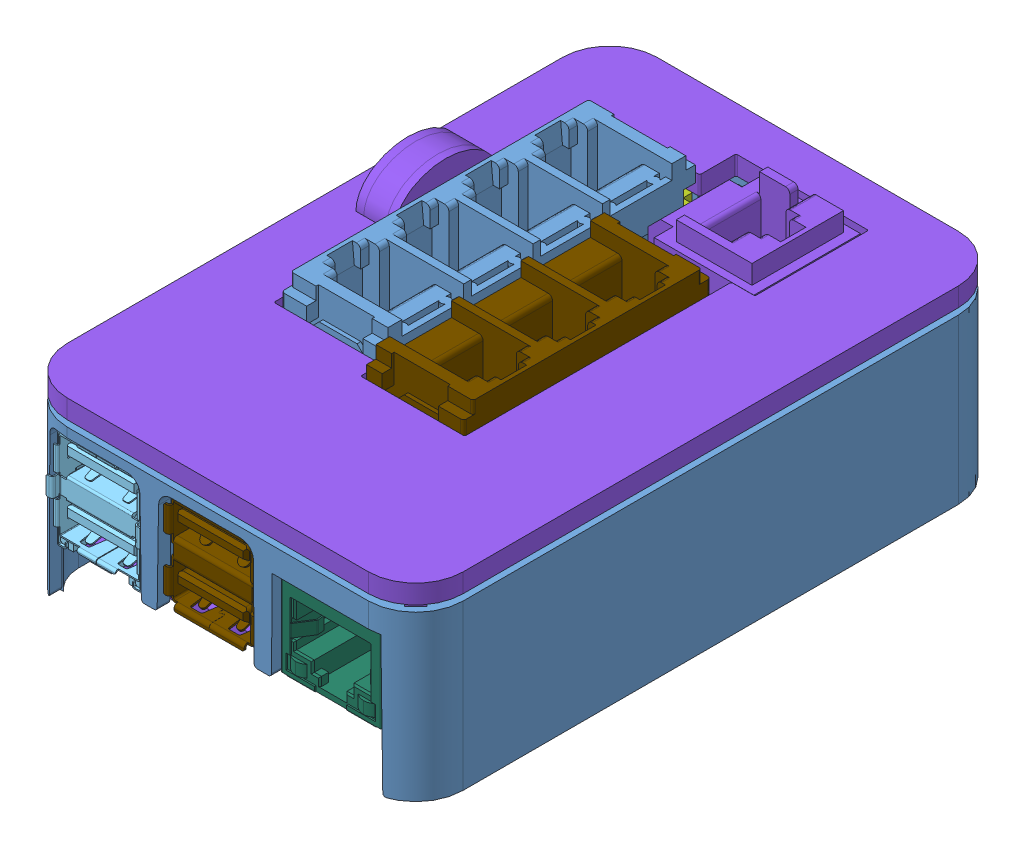
SolidWorks assembly Assemblage_2print, configuration Défaut. Lengths in mm.
Overall size (62.75 36.13 93.5).
237 component instances, 44 part files, 9 mates.
Components (placement in the parent):
- RPI4_Canakit_Case-1: RPI4_Canakit_Case [Défaut] at (-18.9096 -7.6584 0) size (62.75 26 93.5)
- Mainboard_Rpi4-1: Mainboard_Rpi4 [Défaut] at (4.6154 9.8935 -38.925) x (0 0 1) z (0 1 0) size (66 57.75 22.04)
  - Mainboard_Rpi4.step-1: Mainboard_Rpi4.step [Défaut] at origin size (66 57.75 22.04)
    - J5.step-1: J5.step [Défaut] at origin size (50.8 7.2 4.95)
      - m20-7812045_asm.step-1: m20-7812045_asm.step [Défaut] at (4.8701 0.0001 -1.7297) x (1 0 0) z (0 1 0) size (50.8 4.95 7.2)
        - M20-78120_MOULD.step-1: M20-78120_MOULD.step [Défaut] at origin size (50.8 4.95 5.08)
        - M20-781_CONTACT.step-1: M20-781_CONTACT.step [Défaut] at (-0.75 1.3 -2.135) size (1.5 2.8 2.83)
        - M20-781_CONTACT.step-2: M20-781_CONTACT.step [Défaut] at (1.79 1.3 -2.135) size (1.5 2.8 2.83)
        - M20-781_CONTACT.step-3: M20-781_CONTACT.step [Défaut] at (4.33 1.3 -2.135) size (1.5 2.8 2.83)
        - M20-781_CONTACT.step-4: M20-781_CONTACT.step [Défaut] at (6.87 1.3 -2.135) size (1.5 2.8 2.83)
        - M20-781_CONTACT.step-5: M20-781_CONTACT.step [Défaut] at (9.41 1.3 -2.135) size (1.5 2.8 2.83)
        - M20-781_CONTACT.step-6: M20-781_CONTACT.step [Défaut] at (11.95 1.3 -2.135) size (1.5 2.8 2.83)
        - M20-781_CONTACT.step-7: M20-781_CONTACT.step [Défaut] at (14.49 1.3 -2.135) size (1.5 2.8 2.83)
        - M20-781_CONTACT.step-8: M20-781_CONTACT.step [Défaut] at (17.03 1.3 -2.135) size (1.5 2.8 2.83)
        - M20-781_CONTACT.step-9: M20-781_CONTACT.step [Défaut] at (19.57 1.3 -2.135) size (1.5 2.8 2.83)
        - M20-781_CONTACT.step-10: M20-781_CONTACT.step [Défaut] at (22.11 1.3 -2.135) size (1.5 2.8 2.83)
        - M20-781_CONTACT.step-11: M20-781_CONTACT.step [Défaut] at (24.65 1.3 -2.135) size (1.5 2.8 2.83)
        - M20-781_CONTACT.step-12: M20-781_CONTACT.step [Défaut] at (27.19 1.3 -2.135) size (1.5 2.8 2.83)
        - M20-781_CONTACT.step-13: M20-781_CONTACT.step [Défaut] at (29.73 1.3 -2.135) size (1.5 2.8 2.83)
        - M20-781_CONTACT.step-14: M20-781_CONTACT.step [Défaut] at (32.27 1.3 -2.135) size (1.5 2.8 2.83)
        - M20-781_CONTACT.step-15: M20-781_CONTACT.step [Défaut] at (34.81 1.3 -2.135) size (1.5 2.8 2.83)
        - M20-781_CONTACT.step-16: M20-781_CONTACT.step [Défaut] at (37.35 1.3 -2.135) size (1.5 2.8 2.83)
        - M20-781_CONTACT.step-17: M20-781_CONTACT.step [Défaut] at (39.89 1.3 -2.135) size (1.5 2.8 2.83)
        - M20-781_CONTACT.step-18: M20-781_CONTACT.step [Défaut] at (42.43 1.3 -2.135) size (1.5 2.8 2.83)
        - M20-781_CONTACT.step-19: M20-781_CONTACT.step [Défaut] at (44.97 1.3 -2.135) size (1.5 2.8 2.83)
        - M20-781_CONTACT.step-20: M20-781_CONTACT.step [Défaut] at (47.51 1.3 -2.135) size (1.5 2.8 2.83)
        - M20-781_CONTACT.step-21: M20-781_CONTACT.step [Défaut] at (0.75 1.3 2.135) x (-1 0 0) z (0 0 -1) size (1.5 2.8 2.83)
        - M20-781_CONTACT.step-22: M20-781_CONTACT.step [Défaut] at (3.29 1.3 2.135) x (-1 0 0) z (0 0 -1) size (1.5 2.8 2.83)
        - M20-781_CONTACT.step-23: M20-781_CONTACT.step [Défaut] at (5.83 1.3 2.135) x (-1 0 0) z (0 0 -1) size (1.5 2.8 2.83)
        - M20-781_CONTACT.step-24: M20-781_CONTACT.step [Défaut] at (8.37 1.3 2.135) x (-1 0 0) z (0 0 -1) size (1.5 2.8 2.83)
        - M20-781_CONTACT.step-25: M20-781_CONTACT.step [Défaut] at (10.91 1.3 2.135) x (-1 0 0) z (0 0 -1) size (1.5 2.8 2.83)
        - M20-781_CONTACT.step-26: M20-781_CONTACT.step [Défaut] at (13.45 1.3 2.135) x (-1 0 0) z (0 0 -1) size (1.5 2.8 2.83)
        - M20-781_CONTACT.step-27: M20-781_CONTACT.step [Défaut] at (15.99 1.3 2.135) x (-1 0 0) z (0 0 -1) size (1.5 2.8 2.83)
        - M20-781_CONTACT.step-28: M20-781_CONTACT.step [Défaut] at (18.53 1.3 2.135) x (-1 0 0) z (0 0 -1) size (1.5 2.8 2.83)
        - M20-781_CONTACT.step-29: M20-781_CONTACT.step [Défaut] at (21.07 1.3 2.135) x (-1 0 0) z (0 0 -1) size (1.5 2.8 2.83)
        - M20-781_CONTACT.step-30: M20-781_CONTACT.step [Défaut] at (23.61 1.3 2.135) x (-1 0 0) z (0 0 -1) size (1.5 2.8 2.83)
        - M20-781_CONTACT.step-31: M20-781_CONTACT.step [Défaut] at (26.15 1.3 2.135) x (-1 0 0) z (0 0 -1) size (1.5 2.8 2.83)
        - M20-781_CONTACT.step-32: M20-781_CONTACT.step [Défaut] at (28.69 1.3 2.135) x (-1 0 0) z (0 0 -1) size (1.5 2.8 2.83)
        - M20-781_CONTACT.step-33: M20-781_CONTACT.step [Défaut] at (31.23 1.3 2.135) x (-1 0 0) z (0 0 -1) size (1.5 2.8 2.83)
        - M20-781_CONTACT.step-34: M20-781_CONTACT.step [Défaut] at (33.77 1.3 2.135) x (-1 0 0) z (0 0 -1) size (1.5 2.8 2.83)
        - M20-781_CONTACT.step-35: M20-781_CONTACT.step [Défaut] at (36.31 1.3 2.135) x (-1 0 0) z (0 0 -1) size (1.5 2.8 2.83)
        - M20-781_CONTACT.step-36: M20-781_CONTACT.step [Défaut] at (38.85 1.3 2.135) x (-1 0 0) z (0 0 -1) size (1.5 2.8 2.83)
        - M20-781_CONTACT.step-37: M20-781_CONTACT.step [Défaut] at (41.39 1.3 2.135) x (-1 0 0) z (0 0 -1) size (1.5 2.8 2.83)
        - M20-781_CONTACT.step-38: M20-781_CONTACT.step [Défaut] at (43.93 1.3 2.135) x (-1 0 0) z (0 0 -1) size (1.5 2.8 2.83)
        - M20-781_CONTACT.step-39: M20-781_CONTACT.step [Défaut] at (46.47 1.3 2.135) x (-1 0 0) z (0 0 -1) size (1.5 2.8 2.83)
        - M20-781_CONTACT.step-40: M20-781_CONTACT.step [Défaut] at (49.01 1.3 2.135) x (-1 0 0) z (0 0 -1) size (1.5 2.8 2.83)
    - C3.step-1: C3.step [Défaut] at origin size (2.2 1.45 1.4)
      - 870407824.step-1: 870407824.step [Défaut] at (-0.508 -11.732 -2.9519) size (2.2 1.45 1.4)
        - Extruded.step-1: Extruded.step [Défaut] at origin size (2.2 1.45 1.4)
    - C2.step-1: C2.step [Défaut] at origin size (2.2 1.45 1.4)
      - 870407824.step-1: 870407824.step [Défaut] at (50.8 -29.718 -2.9519) size (2.2 1.45 1.4)
        - Extruded.step-1: Extruded.step [Défaut] at origin size (2.2 1.45 1.4)
    - U10.step-1: U10.step [Défaut] at origin size (2 2 0.8)
      - 870408096.step-1: 870408096.step [Défaut] at (7.747 -16.873 -2.4519) size (2 2 0.8)
        - Extruded-0.step-1: Extruded-0.step [Défaut] at origin size (2 2 0.8)
    - U9.step-1: U9.step [Défaut] at origin size (2 2 0.8)
      - 870408096.step-1: 870408096.step [Défaut] at (11.049 -16.873 -2.4519) size (2 2 0.8)
        - Extruded-0.step-1: Extruded-0.step [Défaut] at origin size (2 2 0.8)
    - U8.step-1: U8.step [Défaut] at origin size (2 2 0.8)
      - 870408096.step-1: 870408096.step [Défaut] at (4.445 -16.873 -2.4519) size (2 2 0.8)
        - Extruded-0.step-1: Extruded-0.step [Défaut] at origin size (2 2 0.8)
    - R3.step-1: R3.step [Défaut] at origin size (1.4 2.15 0.7)
      - 870408368.step-1: 870408368.step [Défaut] at (8.89 -9.779 -2.2519) size (1.4 2.15 0.7)
        - Extruded-1.step-1: Extruded-1.step [Défaut] at origin size (1.4 2.15 0.7)
    - Q8.step-1: Q8.step [Défaut] at origin size (2.2 1.35 1)
      - 870406736.step-1: 870406736.step [Défaut] at (1.524 -8.938 -2.6519) size (2.2 1.35 1)
        - Extruded-2.step-1: Extruded-2.step [Défaut] at origin size (2.2 1.35 1)
    - J3.step-1: J3.step [Défaut] at origin size (20.9 19.8 19.5)
      - TM3RA-88_RGB13278208.step-1: TM3RA-88_RGB13278208.step [Défaut] at (8.2551 -24.0349 12.5) x (1 0 0) z (0 0 1) size (20.9 19.8 19.5)
    - U7.step-1: U7.step [Défaut] at origin size (2 2 0.8)
      - 870408096.step-1: 870408096.step [Défaut] at (26.369 -39.41 -2.4519) size (2 2 0.8)
        - Extruded-0.step-1: Extruded-0.step [Défaut] at origin size (2 2 0.8)
    - U6.step-1: U6.step [Défaut] at origin size (2 2 0.8)
      - 870408096.step-1: 870408096.step [Défaut] at (49.099 -15.349 -2.4519) size (2 2 0.8)
        - Extruded-0.step-1: Extruded-0.step [Défaut] at origin size (2 2 0.8)
    - U5.step-1: U5.step [Défaut] at origin size (2 2 0.8)
      - 870408096.step-1: 870408096.step [Défaut] at (37.291 -39.41 -2.4519) size (2 2 0.8)
        - Extruded-0.step-1: Extruded-0.step [Défaut] at origin size (2 2 0.8)
    - U4.step-1: U4.step [Défaut] at origin size (2 2 0.8)
      - 870408096.step-1: 870408096.step [Défaut] at (38.05 -15.349 -2.4519) size (2 2 0.8)
        - Extruded-0.step-1: Extruded-0.step [Défaut] at origin size (2 2 0.8)
    - U3.step-1: U3.step [Défaut] at origin size (2 2 0.8)
      - 870408096.step-1: 870408096.step [Défaut] at (15.32 -39.41 -2.4519) size (2 2 0.8)
        - Extruded-0.step-1: Extruded-0.step [Défaut] at origin size (2 2 0.8)
    - U2.step-1: U2.step [Défaut] at origin size (2 2 0.8)
      - 870408096.step-1: 870408096.step [Défaut] at (48.34 -39.41 -2.4519) size (2 2 0.8)
        - Extruded-0.step-1: Extruded-0.step [Défaut] at origin size (2 2 0.8)
    - U1.step-1: U1.step [Défaut] at origin size (2 2 0.8)
      - 870408096.step-1: 870408096.step [Défaut] at (27.128 -15.349 -2.4519) size (2 2 0.8)
        - Extruded-0.step-1: Extruded-0.step [Défaut] at origin size (2 2 0.8)
    - Q7.step-1: Q7.step [Défaut] at origin size (1.35 2.2 1)
      - 870407280.step-1: 870407280.step [Défaut] at (10.24 -39.16 -2.6519) size (1.35 2.2 1)
        - Extruded-3.step-1: Extruded-3.step [Défaut] at origin size (1.35 2.2 1)
    - Q6.step-1: Q6.step [Défaut] at origin size (1.35 2.2 1)
      - 870407280.step-1: 870407280.step [Défaut] at (21.289 -39.16 -2.6519) size (1.35 2.2 1)
        - Extruded-3.step-1: Extruded-3.step [Défaut] at origin size (1.35 2.2 1)
    - Q5.step-1: Q5.step [Défaut] at origin size (1.35 2.2 1)
      - 870407280.step-1: 870407280.step [Défaut] at (32.211 -39.16 -2.6519) size (1.35 2.2 1)
        - Extruded-3.step-1: Extruded-3.step [Défaut] at origin size (1.35 2.2 1)
    - Q4.step-1: Q4.step [Défaut] at origin size (1.35 2.2 1)
      - 870407280.step-1: 870407280.step [Défaut] at (43.26 -39.16 -2.6519) size (1.35 2.2 1)
        - Extruded-3.step-1: Extruded-3.step [Défaut] at origin size (1.35 2.2 1)
    - Q3.step-1: Q3.step [Défaut] at origin size (1.35 2.2 1)
      - 870407280.step-1: 870407280.step [Défaut] at (54.179 -15.599 -2.6519) size (1.35 2.2 1)
        - Extruded-3.step-1: Extruded-3.step [Défaut] at origin size (1.35 2.2 1)
    - Q2.step-1: Q2.step [Défaut] at origin size (1.35 2.2 1)
      - 870407280.step-1: 870407280.step [Défaut] at (43.13 -15.599 -2.6519) size (1.35 2.2 1)
        - Extruded-3.step-1: Extruded-3.step [Défaut] at origin size (1.35 2.2 1)
    - Q1.step-1: Q1.step [Défaut] at origin size (1.35 2.2 1)
      - 870407280.step-1: 870407280.step [Défaut] at (32.208 -15.599 -2.6519) size (1.35 2.2 1)
        - Extruded-3.step-1: Extruded-3.step [Défaut] at origin size (1.35 2.2 1)
    - R2.step-1: R2.step [Défaut] at origin size (2.15 1.4 0.7)
      - 870406464.step-1: 870406464.step [Défaut] at (43.514 -45.974 -2.2519) size (2.15 1.4 0.7)
        - Extruded-4.step-1: Extruded-4.step [Défaut] at origin size (2.15 1.4 0.7)
    - R1.step-1: R1.step [Défaut] at origin size (2.15 1.4 0.7)
      - 870406464.step-1: 870406464.step [Défaut] at (43.514 -48.26 -2.2519) size (2.15 1.4 0.7)
        - Extruded-4.step-1: Extruded-4.step [Défaut] at origin size (2.15 1.4 0.7)
    - U11.step-1: U11.step [Défaut] at origin size (4.91 6.03 1.75)
      - 873278928.step-1: 873278928.step [Défaut] at (0.635 -37.084 -1.5519) x (0 -1 0) z (0 0 -1) size (6.03 4.9 1.75)
        - Body.step-1: Body.step [Défaut] at (-1.95 -2.45 0) size (3.91 4.9 1.65)
          - Open_CASCADE_STEP_translator_6.8_10.2.1.step-1: Open_CASCADE_STEP_translator_6.8_10.2.1.step [Défaut] at origin size (3.91 4.9 1.65)
        - Open_CASCADE_STEP_translator_6.8_10.1.step-1: Open_CASCADE_STEP_translator_6.8_10.1.step [Défaut] at (-1.95 -2.45 0.001) size (0.5 0.5 0.01)
        - Leader.step-1: Leader.step [Défaut] at (-1.95 -1.905 0) x (-1 0 0) z (0 0 1) size (1.06 0.41 0.97)
        - Leader.step-2: Leader.step [Défaut] at (-1.95 -0.635 0) x (-1 0 0) z (0 0 1) size (1.06 0.41 0.97)
        - Leader.step-3: Leader.step [Défaut] at (-1.95 0.635 0) x (-1 0 0) z (0 0 1) size (1.06 0.41 0.97)
        - Leader.step-4: Leader.step [Défaut] at (-1.95 1.905 0) x (-1 0 0) z (0 0 1) size (1.06 0.41 0.97)
        - Leader.step-5: Leader.step [Défaut] at (1.95 -1.905 0) size (1.06 0.41 0.97)
        - Leader.step-6: Leader.step [Défaut] at (1.95 -0.635 0) size (1.06 0.41 0.97)
        - Leader.step-7: Leader.step [Défaut] at (1.95 0.635 0) size (1.06 0.41 0.97)
        - Leader.step-8: Leader.step [Défaut] at (1.95 1.905 0) size (1.06 0.41 0.97)
    - J4.step-1: J4.step [Défaut] at origin size (15.42 4.78 16.81)
      - BS-1225-PC.step-1: BS-1225-PC.step [Défaut] at (29.2101 -47.371 0) x (-1 0 0) z (0 1 0) size (15.42 16.81 4.78)
    - Cx2.step-1: Cx2.step [Défaut] at origin size (1.45 2.2 1.4)
      - 870404832.step-1: 870404832.step [Défaut] at (0.705 -26.66 -2.9519) size (1.45 2.2 1.4)
        - Extruded-5.step-1: Extruded-5.step [Défaut] at origin size (1.45 2.2 1.4)
    - Cx1.step-1: Cx1.step [Défaut] at origin size (1.45 2.2 1.4)
      - 870404832.step-1: 870404832.step [Défaut] at (-1.795 -26.66 -2.9519) size (1.45 2.2 1.4)
        - Extruded-5.step-1: Extruded-5.step [Défaut] at origin size (1.45 2.2 1.4)
    - C1.step-1: C1.step [Défaut] at origin size (2.2 1.45 1.4)
      - 870407824.step-1: 870407824.step [Défaut] at (-0.545 -42.926 -2.9519) size (2.2 1.45 1.4)
        - Extruded.step-1: Extruded.step [Défaut] at origin size (2.2 1.45 1.4)
    - U12.step-1: U12.step [Défaut] at origin size (3.7 2 0.9)
      - 873282384.step-1: 873282384.step [Défaut] at (-0.545 -30.9968 -1.5519) x (-1 0 0) z (0 0 -1) size (3.7 2 0.9)
        - Body-6.step-1: Body-6.step [Défaut] at (-1.65 -0.8 0) size (3.3 1.6 0.9)
        - bigPin.step-1: bigPin.step [Défaut] at (-1.85 -1 -0.0033) size (1.2 2 0.01)
        - bigPin.step-2: bigPin.step [Défaut] at (0.65 -1 -0.0033) size (1.2 2 0.01)
    - J1.step-1: J1.step [Défaut] at origin size (39.2 15.4 22.04)
      - TM2RE-1818(50)_RGB13278208.step-1: TM2RE-1818(50)_RGB13278208.step [Défaut] at (39.3359 -11.3181 16) x (1 0 0) z (0 0 1) size (39.2 15.4 22.04)
        - TM2RE-1818(50).step-1: TM2RE-1818(50).step [Défaut] at (0 -7.7 0) size (39.2 15.4 22.04)
    - J2.step-1: J2.step [Défaut] at origin size (50.2 15.4 22.04)
      - TM2RE-2424_RGB13278208.step-1: TM2RE-2424_RGB13278208.step [Défaut] at (47.0601 -35.774 16) x (-1 0 0) z (0 0 1) size (50.2 15.4 22.04)
    - P2.step-1: P2.step [Défaut] at origin size (2.54 2.54 5.55)
      - 870406192.step-1: 870406192.step [Défaut] at (0 -4.826 0) size (2.54 2.54 5.55)
        - Extruded-7.step-1: Extruded-7.step [Défaut] at origin size (2.54 2.54 5.55)
    - R4.step-1: R4.step [Défaut] at origin size (1.7 0.95 0.55)
      - 870422376.step-1: 870422376.step [Défaut] at (50.8 -27.7876 -2.1019) size (1.7 0.95 0.55)
        - Extruded-8.step-1: Extruded-8.step [Défaut] at origin size (1.7 0.95 0.55)
    - R5.step-1: R5.step [Défaut] at origin size (1.7 0.95 0.55)
      - 870422376.step-1: 870422376.step [Défaut] at (47.498 -27.7876 -2.1019) size (1.7 0.95 0.55)
        - Extruded-8.step-1: Extruded-8.step [Défaut] at origin size (1.7 0.95 0.55)
    - R6.step-1: R6.step [Défaut] at origin size (1.7 0.95 0.55)
      - 870422376.step-1: 870422376.step [Défaut] at (31.115 -12.7 -2.1019) size (1.7 0.95 0.55)
        - Extruded-8.step-1: Extruded-8.step [Défaut] at origin size (1.7 0.95 0.55)
    - R7.step-1: R7.step [Défaut] at origin size (1.7 0.95 0.55)
      - 870422376.step-1: 870422376.step [Défaut] at (26.162 -12.7 -2.1019) size (1.7 0.95 0.55)
        - Extruded-8.step-1: Extruded-8.step [Défaut] at origin size (1.7 0.95 0.55)
    - R8.step-1: R8.step [Défaut] at origin size (1.7 0.95 0.55)
      - 870422376.step-1: 870422376.step [Défaut] at (42.037 -12.7148 -2.1019) size (1.7 0.95 0.55)
        - Extruded-8.step-1: Extruded-8.step [Défaut] at origin size (1.7 0.95 0.55)
    - R9.step-1: R9.step [Défaut] at origin size (1.7 0.95 0.55)
      - 870422376.step-1: 870422376.step [Défaut] at (36.97 -12.7 -2.1019) size (1.7 0.95 0.55)
        - Extruded-8.step-1: Extruded-8.step [Défaut] at origin size (1.7 0.95 0.55)
    - R10.step-1: R10.step [Défaut] at origin size (1.7 0.95 0.55)
      - 870422376.step-1: 870422376.step [Défaut] at (52.844 -12.7148 -2.1019) size (1.7 0.95 0.55)
        - Extruded-8.step-1: Extruded-8.step [Défaut] at origin size (1.7 0.95 0.55)
    - R11.step-1: R11.step [Défaut] at origin size (1.7 0.95 0.55)
      - 870422376.step-1: 870422376.step [Défaut] at (48.073 -12.7 -2.1019) size (1.7 0.95 0.55)
        - Extruded-8.step-1: Extruded-8.step [Défaut] at origin size (1.7 0.95 0.55)
    - R12.step-1: R12.step [Défaut] at origin size (1.7 0.95 0.55)
      - 870422376.step-1: 870422376.step [Défaut] at (43.815 -41.402 -2.1019) size (1.7 0.95 0.55)
        - Extruded-8.step-1: Extruded-8.step [Défaut] at origin size (1.7 0.95 0.55)
    - R13.step-1: R13.step [Défaut] at origin size (1.7 0.95 0.55)
      - 870422376.step-1: 870422376.step [Défaut] at (49.093 -42.585 -2.1019) size (1.7 0.95 0.55)
        - Extruded-8.step-1: Extruded-8.step [Défaut] at origin size (1.7 0.95 0.55)
    - R14.step-1: R14.step [Défaut] at origin size (1.7 0.95 0.55)
      - 870422376.step-1: 870422376.step [Défaut] at (32.766 -41.402 -2.1019) size (1.7 0.95 0.55)
        - Extruded-8.step-1: Extruded-8.step [Défaut] at origin size (1.7 0.95 0.55)
    - R15.step-1: R15.step [Défaut] at origin size (1.7 0.95 0.55)
      - 870422376.step-1: 870422376.step [Défaut] at (38.044 -42.2262 -2.1019) size (1.7 0.95 0.55)
        - Extruded-8.step-1: Extruded-8.step [Défaut] at origin size (1.7 0.95 0.55)
    - R16.step-1: R16.step [Défaut] at origin size (1.7 0.95 0.55)
      - 870422376.step-1: 870422376.step [Défaut] at (21.857 -41.402 -2.1019) size (1.7 0.95 0.55)
        - Extruded-8.step-1: Extruded-8.step [Défaut] at origin size (1.7 0.95 0.55)
    - R17.step-1: R17.step [Défaut] at origin size (1.7 0.95 0.55)
      - 870422376.step-1: 870422376.step [Défaut] at (27.122 -42.2262 -2.1019) size (1.7 0.95 0.55)
        - Extruded-8.step-1: Extruded-8.step [Défaut] at origin size (1.7 0.95 0.55)
    - R18.step-1: R18.step [Défaut] at origin size (1.7 0.95 0.55)
      - 870422376.step-1: 870422376.step [Défaut] at (10.821 -41.402 -2.1019) size (1.7 0.95 0.55)
        - Extruded-8.step-1: Extruded-8.step [Défaut] at origin size (1.7 0.95 0.55)
    - R19.step-1: R19.step [Défaut] at origin size (1.7 0.95 0.55)
      - 870422376.step-1: 870422376.step [Défaut] at (16.073 -42.2262 -2.1019) size (1.7 0.95 0.55)
        - Extruded-8.step-1: Extruded-8.step [Défaut] at origin size (1.7 0.95 0.55)
    - R20.step-1: R20.step [Défaut] at origin size (0.95 1.7 0.55)
      - 870405920.step-1: 870405920.step [Défaut] at (13.2927 -21.987 -2.1019) size (0.95 1.7 0.55)
        - Extruded-9.step-1: Extruded-9.step [Défaut] at origin size (0.95 1.7 0.55)
    - R21.step-1: R21.step [Défaut] at origin size (0.95 1.7 0.55)
      - 870405920.step-1: 870405920.step [Défaut] at (14.986 -21.987 -2.1019) size (0.95 1.7 0.55)
        - Extruded-9.step-1: Extruded-9.step [Défaut] at origin size (0.95 1.7 0.55)
    - U13.step-1: U13.step [Défaut] at origin size (8.49 8.49 1)
      - 870411632.step-1: 870411632.step [Défaut] at (17.055 -9.1329 -2.5519) size (8.49 8.49 1)
        - Extruded-10.step-1: Extruded-10.step [Défaut] at origin size (8.49 8.49 1)
    - Free-Models.step-1: Free-Models.step [Défaut] at origin size (12.5 1.6 12.5)
      - 873281360.step-1: 873281360.step [Défaut] at (29.21 -48.336 7.5) x (-1 0 0) z (0 1 0) size (12.5 12.5 1.6)
        - Cylinder.step-1: Cylinder.step [Défaut] at origin size (12.5 12.5 1.6)
    - Board.step-1: Board.step [Défaut] at (0 0 -1.5519) size (66 57.75 1.55)
- Raspberry Pi 4 Model B-1: Raspberry Pi 4 Model B [Défaut] at (-19.8846 -0.4584 0.075) x (0 0 1) z (-1 0 0) size (89 19.92 58.4)
  - Raspberry Pi 4 Model B.STEP-1: Raspberry Pi 4 Model B.STEP [Défaut] at origin size (89 19.92 58.4)
    - PCB, RPi4ModelB.STEP-1: PCB, RPi4ModelB.STEP [Défaut] at origin size (85 1.6 56)
    - Broadcom BCM2711B0 CPU, RPi4ModelB.STEP-1: Broadcom BCM2711B0 CPU, RPi4ModelB.STEP [Défaut] at (-13.25 0.8 -4.5) size (15 2.3 15)
    - 2.54 mm DUPONT MALE PIN HEADER, POE, 2X2, RPi4ModelB.STEP-1: 2.54 mm DUPONT MALE PIN HEADER, POE, 2X2, RPi4ModelB.STEP [Défaut] at (19 0.8 -18.36) size (5.08 11.3 5.08)
    - 2.54 mm DUPONT MALE PIN HEADER, IO, 2X20, RPi4ModelB.STEP-1: 2.54 mm DUPONT MALE PIN HEADER, IO, 2X20, RPi4ModelB.STEP [Défaut] at (-10 0.8 -24.5) size (50.8 11.3 5.08)
    - Camera Connector, RPi4ModelB.STEP-1: Camera Connector, RPi4ModelB.STEP [Défaut] at (4 0.8 16.5) x (0 0 -1) z (1 0 0) size (22.4 5.68 5.07)
    - Microphone Plug, RPi4ModelB.STEP-1: Microphone Plug, RPi4ModelB.STEP [Défaut] at (11.5 0.8 21.65) size (7.23 7.55 15)
    - Display Connector, RPi4ModelB.STEP-1: Display Connector, RPi4ModelB.STEP [Défaut] at (-38.5 0.8 0) x (0 0 1) z (-1 0 0) size (22.4 5.68 5.07)
    - Gigabit Ethernet Port, RPi4ModelB.STEP-1: Gigabit Ethernet Port, RPi4ModelB.STEP [Défaut] at (45.5 7.55 -17.75) x (0 0 -1) z (1 0 0) size (16.33 17.24 21.6)
    - Female Micro HDMI Connector, RPi4ModelB.STEP-1: Female Micro HDMI Connector, RPi4ModelB.STEP [Défaut] at (-3 0.8 27.3875) size (6.5 3.51 7.5)
    - Female Micro HDMI Connector, RPi4ModelB.STEP-2: Female Micro HDMI Connector, RPi4ModelB.STEP [Défaut] at (-16.5 0.8 27.3875) size (6.5 3.51 7.5)
    - Female USB Type C Connector, RPi4ModelB.STEP-1: Female USB Type C Connector, RPi4ModelB.STEP [Défaut] at (-31.3 0.8 26.5419) size (8.94 3.96 7.9)
    - 2X USB3.0 PORTS, RPi4ModelB.STEP-1: 2X USB3.0 PORTS, RPi4ModelB.STEP [Défaut] at (37.07 0.8 1) size (17.48 19.42 15.69)
    - 91D77 D9WHV 778K, 4 GB LPDDR4 SDRAM, RPi4ModelB.STEP-1: 91D77 D9WHV 778K, 4 GB LPDDR4 SDRAM, RPi4ModelB.STEP [Défaut] at (2.25 0.8 -4.5) size (10 0.8 14.5)
    - Cypress CYW43455 Wireless Module Cover, RPi4ModelB.STEP-1: Cypress CYW43455 Wireless Module Cover, RPi4ModelB.STEP [Défaut] at (-30.5 0.8 -14.5) size (11 1.6 13)
    - SD Card Slot, RPi4ModelB.STEP-1: SD Card Slot, RPi4ModelB.STEP [Défaut] at (-35.3 -0.8 0) x (0 0 -1) z (-1 0 0) size (11.95 1.45 11.4)
    - VIA VL805 PCIe USB 3.0 controller, RPi4ModelB.STEP-1: VIA VL805 PCIe USB 3.0 controller, RPi4ModelB.STEP [Défaut] at (17.5 0.8 4) size (8.8 0.8 8.8)
    - 2X USB2.0 PORTS, RPi4ModelB.STEP-1: 2X USB2.0 PORTS, RPi4ModelB.STEP [Défaut] at (37.065 0.65 19) size (17.87 19.17 15.35)
    - Broadcom BCM54213PE Gigabit Ethernet Transceiver, RPi4ModelB.STEP-1: Broadcom BCM54213PE Gigabit Ethernet Transceiver, RPi4ModelB.STEP [Défaut] at (16.5 0.8 -10) size (6.8 1 6.8)
    - MxL7704 Universal PMIC, RPi4ModelB.STEP-1: MxL7704 Universal PMIC, RPi4ModelB.STEP [Défaut] at (-32.5 0.8 16) size (5.4 0.8 5.4)
- RPI4_Canakit_cover-1: RPI4_Canakit_cover [Défaut] at (-18.9096 20.8416 0) x (-1 0 0) z (0 0 1) size (62.75 15.93 93.5)
Mates (geometry in assembly coordinates):
- Coaxiale1: concentric aligned: cylinder of RPI4_Canakit_Case-1 through (12.4664 3.3416 11.575) axis (-1 0 0) radius 3.5; cylinder of Raspberry Pi 4 Model B-1/Raspberry Pi 4 Model B.STEP-1/Microphone Plug, RPi4ModelB.STEP-1 through (-47.7846 3.3416 11.575) axis (-1 0 0) radius 3
- Parallèle1: parallel aligned: plane of RPI4_Canakit_Case-1 through (-18.9096 -7.6584 0) normal (0 -1 0); plane of Raspberry Pi 4 Model B-1/Raspberry Pi 4 Model B.STEP-1/PCB, RPi4ModelB.STEP-1 through (-19.8846 -1.2584 0.075) normal (0 -1 0)
- Coïncidente4: coincident aligned: plane of RPI4_Canakit_Case-1 through (-50.2846 18.3416 -46.75) normal (-1 0 0); plane of Raspberry Pi 4 Model B-1/Raspberry Pi 4 Model B.STEP-1/Microphone Plug, RPi4ModelB.STEP-1 through (-50.2846 0.6406 8.874) normal (-1 0 0)
- Coaxiale2: concentric anti-aligned: cylinder of Mainboard_Rpi4-1/Mainboard_Rpi4.step-1/Board.step-1 through (4.6154 8.3416 19.075) axis (0 -1 0) radius 1.375; cylinder of Raspberry Pi 4 Model B-1/Raspberry Pi 4 Model B.STEP-1/PCB, RPi4ModelB.STEP-1 through (4.6154 0.3416 19.075) axis (0 1 0) radius 1.35
- Parallèle3: parallel anti-aligned: plane of RPI4_Canakit_Case-1 through (10.4654 -7.6594 -39.25) normal (-1 0 0); plane of Mainboard_Rpi4-1/Mainboard_Rpi4.step-1/Board.step-1 through (9.8654 8.3416 16.575) normal (1 0 0)
- Coïncidente7: coincident anti-aligned: plane of RPI4_Canakit_Case-1 through (-42.7846 8.3416 -39.25) normal (0 1 0); plane of Mainboard_Rpi4-1/Mainboard_Rpi4.step-1/Board.step-1 through (-47.8846 8.3416 -38.425) normal (0 -1 0)
- Distance1: distance = 1 mm anti-aligned: plane of RPI4_Canakit_Case-1 through (-18.9096 18.3416 0) normal (0 1 0); plane of RPI4_Canakit_cover-1 through (4.9654 19.3416 39.25) normal (0 -1 0)
- Largeur1: width anti-aligned: plane of RPI4_Canakit_cover-1 through (-50.2846 19.3416 39.25) normal (-1 0 0); plane of RPI4_Canakit_cover-1 through (12.4654 19.3416 39.25) normal (1 0 0); plane of RPI4_Canakit_Case-1 through (12.4654 18.3416 -46.75) normal (1 0 0); plane of RPI4_Canakit_Case-1 through (-50.2846 18.3416 -46.75) normal (-1 0 0)
- Largeur2: width anti-aligned: plane of RPI4_Canakit_cover-1 through (4.9654 19.3416 -46.75) normal (0 0 -1); plane of RPI4_Canakit_cover-1 through (4.9654 19.3416 46.75) normal (0 0 1); plane of RPI4_Canakit_Case-1 through (-50.2846 18.3416 46.75) normal (0 0 1); plane of RPI4_Canakit_Case-1 through (-50.2846 18.3416 -46.75) normal (0 0 -1)
